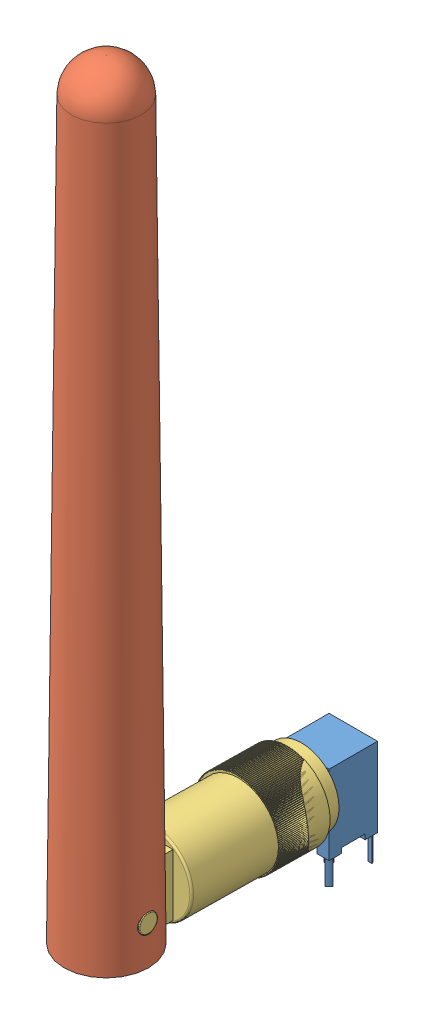
SolidWorks assembly Assem1, configuration Default. Lengths in mm.
Overall size (11.11 105.24 37.61).
6 component instances, 5 part files, 0 mates.
Components (placement in the parent):
- Truangten.step-1: Truangten.step [Default] at (-0.6208 0.2927 12.5083) x (0 0 1) z (0 1 0) size (14.2 7.33 13.53)
- antenna_WiFi_RP-SMA_conn.step-1: antenna_WiFi_RP-SMA_conn.step [Default] at (-0.6199 2.3044 41.4648) x (1 0 0) z (0 1 0) size (11.11 30.9 100.5)
  - ant.step-1: ant.step [Default] at (0 -0.0027 0.0017) size (11 10.91 100)
  - conn_body.step-1: conn_body.step [Default] at (-0.0138 -0.0027 0.0017) size (11.11 29.25 11.01)
  - SMA_threads.step-1: SMA_threads.step [Default] at (-0.0138 -0.0027 0.0017) size (8 3 8)
  - socket.step-1: socket.step [Default] at (-0.0138 -0.2827 0.0017) size (1.27 5.64 1.27)
